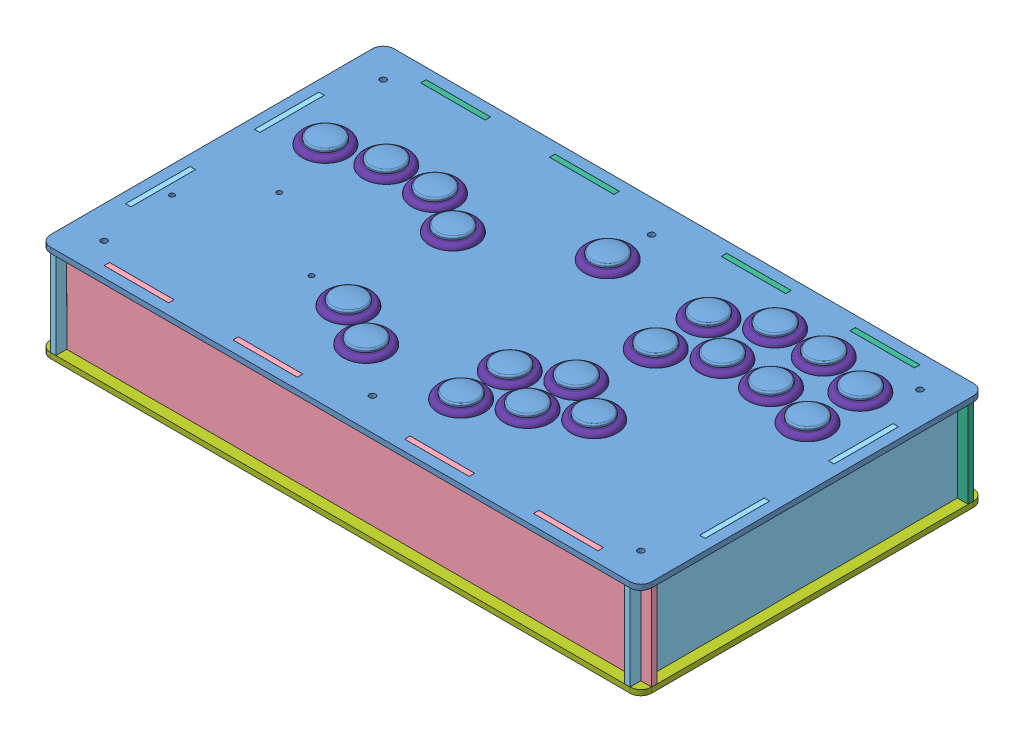
SolidWorks assembly Case v0, configuration Default. Lengths in mm.
Overall size (355.6 62.95 203.2).
164 component instances, 43 part files, 90 mates.
Components (placement in the parent):
- Top Panel-1: Top Panel [Default] at (-41.3019 22.3598 7.6821) size (355.6 3.17 203.2)
- arduino_MEGA2560.STEP-1: arduino_MEGA2560.STEP [Default] at (-106.9007 4.8848 49.2821) x (0 0 1) z (1 0 0) size (53.34 15.25 107.96)
  - MEGAboard.STEP-1: MEGAboard.STEP [Default] at origin size (53.34 1.6 101.6)
  - 47uf CAP Dcase.STEP-1: 47uf CAP Dcase.STEP [Default] at (-9.144 0 -18.415) x (0 0 -1) z (1 0 0) size (7.2 5.81 8)
  - USB SHELL.STEP-1: USB SHELL.STEP [Default] at (-38.02 0.43 6.35) size (14.09 15.2 16.51)
  - USB core.STEP-1: USB core.STEP [Default] at (-38.02 0.43 6.35) size (11.3 10.68 15.75)
  - usb top contact.STEP-1: usb top contact.STEP [Default] at (-36.77 6.52 5.97) size (1 9.67 13.76)
  - usb btm contact.STEP-1: usb btm contact.STEP [Default] at (-36.77 4.84 5.97) size (1 6.84 11.76)
  - usb btm contact.STEP-2: usb btm contact.STEP [Default] at (-39.27 4.84 5.97) size (1 6.84 11.76)
  - usb top contact.STEP-2: usb top contact.STEP [Default] at (-39.27 6.52 5.97) size (1 9.67 13.76)
  - power jack.STEP-1: power jack.STEP [Default] at (-7.675 0 1.905) size (11.2 15.2 15.9)
  - 47uf CAP Dcase.STEP-2: 47uf CAP Dcase.STEP [Default] at (-9.144 0 -25.527) x (0 0 -1) z (1 0 0) size (7.2 5.81 8)
  - crystal.STEP-1: crystal.STEP [Default] at (-26.035 0 -18.415) x (1 0 0) z (0 0 -1) size (4 5 11)
  - 2pin_header__02.STEP-1: 2pin_header__02.STEP [Default] at (-46.23 0 -15.75) size (5 11.75 2.54)
  - reg.STEP-1: reg.STEP [Default] at (-17.78 0 -8.636) size (6.5 1.69 8.3)
  - led.STEP-1: led.STEP [Default] at (-34.29 0 -27.94) x (0 0 1) z (-1 0 0) size (4.01 0.9 1.56)
  - 2pin_header__02.STEP-2: 2pin_header__02.STEP [Default] at (-30.43 0 -64.91) x (0 0 1) z (-1 0 0) size (5 11.75 2.54)
  - 2pin_header__02.STEP-3: 2pin_header__02.STEP [Default] at (-27.89 0 -64.91) x (0 0 1) z (-1 0 0) size (5 11.75 2.54)
  - 2pin_header__02.STEP-4: 2pin_header__02.STEP [Default] at (-25.35 0 -64.91) x (0 0 1) z (-1 0 0) size (5 11.75 2.54)
  - 2pin_header__02.STEP-5: 2pin_header__02.STEP [Default] at (-46.23 0 -18.29) size (5 11.75 2.54)
  - 2pin_header__02.STEP-6: 2pin_header__02.STEP [Default] at (-46.23 0 -20.83) size (5 11.75 2.54)
  - atmega16u2.STEP-1: atmega16u2.STEP [Default] at (-34.671 0.06 -20) x (1 0 0) z (0 0 -1) size (5.5 1.01 5.5)
  - led.STEP-2: led.STEP [Default] at (-36.576 0 -27.94) x (0 0 -1) z (1 0 0) size (4.01 0.9 1.56)
  - led.STEP-3: led.STEP [Default] at (-42.164 0 -27.94) x (0 0 1) z (-1 0 0) size (4.01 0.9 1.56)
  - led.STEP-4: led.STEP [Default] at (-36.83 0 -76.2) x (0 0 1) z (-1 0 0) size (4.01 0.9 1.56)
  - 8 PORT HEADER.STEP-1: 8 PORT HEADER.STEP [Default] at (-50.8 0 -45.72) x (0 0 -1) z (1 0 0) size (20.32 10.51 2.41)
  - 8 PORT HEADER.STEP-2: 8 PORT HEADER.STEP [Default] at (-2.54 0 -27.94) x (0 0 -1) z (1 0 0) size (20.32 10.51 2.41)
  - 8 PORT HEADER.STEP-3: 8 PORT HEADER.STEP [Default] at (-2.54 0 -50.8) x (0 0 -1) z (1 0 0) size (20.32 10.51 2.41)
  - 10 PORT HEADER.STEP-1: 10 PORT HEADER.STEP [Default] at (-50.8 0 -18.796) x (0 0 -1) z (1 0 0) size (25.4 10.51 2.41)
  - 102 RESISTOR PACK.STEP-1: 102 RESISTOR PACK.STEP [Default] at (-36.83 0 -80.645) size (3.2 0.51 3)
  - 102 RESISTOR PACK.STEP-2: 102 RESISTOR PACK.STEP [Default] at (-39.37 0 -27.94) size (3.2 0.51 3)
  - 103 RESISTOR PACK.STEP-1: 103 RESISTOR PACK.STEP [Default] at (-31.115 0 -27.94) size (3.2 0.51 3)
  - 220 RESISTOR PACK.STEP-1: 220 RESISTOR PACK.STEP [Default] at (-37.084 0 -12.065) size (3.2 0.51 3)
  - 16mhz crystal - measured.STEP-1: 16mhz crystal - measured.STEP [Default] at (-14.605 0 -38.354) size (3.4 0.8 2)
  - PADS001.STEP-1: PADS001.STEP [Default] at (-39.878 0.1 -18.288) x (-1 0 0) z (0 0 1) size (4.54 0.1 4.54)
  - 603 cap on pad.STEP-1: 603 cap on pad.STEP [Default] at (-44.45 0 -27.94) x (0 0 -1) z (1 0 0) size (2.76 0.9 1.02)
  - ssot3.STEP-1: ssot3.STEP [Default] at (-25.908 0 -9.144) x (-1 0 0) z (0 0 -1) size (3 1.13 3.09)
  - mf-msmf050-2.STEP-1: mf-msmf050-2.STEP [Default] at (-26.67 0 -4.445) size (6.12 1.1 3.72)
  - 603 cap on pad.STEP-2: 603 cap on pad.STEP [Default] at (-29.337 0 -24.765) x (0 0 1) z (-1 0 0) size (2.76 0.9 1.02)
  - 603 cap on pad.STEP-3: 603 cap on pad.STEP [Default] at (-30.988 0 -12.065) x (0 0 -1) z (1 0 0) size (2.76 0.9 1.02)
  - lmv358.STEP-1: lmv358.STEP [Default] at (-25.146 0 -27.94) size (3.7 1.4 2.9)
  - 603 cap on pad.STEP-4: 603 cap on pad.STEP [Default] at (-17.653 0 -14.351) size (2.76 0.9 1.02)
  - 603 cap on pad.STEP-5: 603 cap on pad.STEP [Default] at (-29.337 0 -12.065) x (0 0 1) z (-1 0 0) size (2.76 0.9 1.02)
  - 603 cap on pad.STEP-6: 603 cap on pad.STEP [Default] at (-29.337 0 -21.59) x (0 0 1) z (-1 0 0) size (2.76 0.9 1.02)
  - 603 cap on pad.STEP-7: 603 cap on pad.STEP [Default] at (-29.337 0 -15.24) x (0 0 1) z (-1 0 0) size (2.76 0.9 1.02)
  - 603 cap on pad.STEP-8: 603 cap on pad.STEP [Default] at (-42.291 0 -12.065) x (0 0 1) z (-1 0 0) size (2.76 0.9 1.02)
  - lp2985dgkr.STEP-1: lp2985dgkr.STEP [Default] at (-21.336 0 -18.415) x (0 0 -1) z (1 0 0) size (5.85 1.1 3)
  - cd1206 diode.STEP-1: cd1206 diode.STEP [Default] at (-14.605 0 -35.56) x (0 0 1) z (-1 0 0) size (2.01 0.96 5)
  - cd1206 diode.STEP-2: cd1206 diode.STEP [Default] at (-46.228 0 -13.081) x (0 0 1) z (-1 0 0) size (2.01 0.96 5)
  - 603 resistor.STEP-1: 603 resistor.STEP [Default] at (-29.337 0 -18.415) x (0 0 1) z (-1 0 0) size (2.36 0.61 1.02)
  - blm21.STEP-1: blm21.STEP [Default] at (-45.085 0 -8.255) x (0 0 -1) z (1 0 0) size (2.78 0.95 1.32)
  - m7 diode.STEP-1: m7 diode.STEP [Default] at (-2.794 0 -21.59) x (0 0 -1) z (1 0 0) size (6.66 2.35 2.5)
  - MLC0603.STEP-1: MLC0603.STEP [Default] at (-34.29 0 -12.065) x (0 0 -1) z (1 0 0) size (2.36 0.6 1.02)
  - MLC0603.STEP-2: MLC0603.STEP [Default] at (-39.878 0 -12.065) x (0 0 -1) z (1 0 0) size (2.36 0.6 1.02)
  - RESET CORE.STEP-1: RESET CORE.STEP [Default] at (-27.94 0.1 -74.168) x (0 0 1) z (-1 0 0) size (6.2 3.1 9.6)
  - RESET.STEP-1: RESET.STEP [Default] at (-27.94 0.1 -74.168) size (7.3 2 6.2)
  - 8 PORT HEADER.STEP-4: 8 PORT HEADER.STEP [Default] at (-2.54 0 -73.66) x (0 0 -1) z (1 0 0) size (20.32 10.51 2.41)
  - 8 PORT HEADER.STEP-5: 8 PORT HEADER.STEP [Default] at (-50.8 0 -68.58) x (0 0 -1) z (1 0 0) size (20.32 10.51 2.41)
  - 603 cap on pad.STEP-9: 603 cap on pad.STEP [Default] at (-21.59 0 -27.94) x (0 0 1) z (-1 0 0) size (2.76 0.9 1.02)
  - 603 cap on pad.STEP-10: 603 cap on pad.STEP [Default] at (-18.288 0 -27.94) x (0 0 1) z (-1 0 0) size (2.76 0.9 1.02)
  - 103 RESISTOR PACK.STEP-2: 103 RESISTOR PACK.STEP [Default] at (-16.51 0 -18.415) size (3.2 0.51 3)
  - 603 cap on pad.STEP-11: 603 cap on pad.STEP [Default] at (-17.145 0 -21.59) x (0 0 -1) z (1 0 0) size (2.76 0.9 1.02)
  - 603 cap on pad.STEP-12: 603 cap on pad.STEP [Default] at (-39.37 0 -58.928) x (0 0 1) z (-1 0 0) size (2.76 0.9 1.02)
  - 603 cap on pad.STEP-13: 603 cap on pad.STEP [Default] at (-14.605 0 -33.528) size (2.76 0.9 1.02)
  - 603 resistor.STEP-2: 603 resistor.STEP [Default] at (-14.605 0 -40.513) x (-1 0 0) z (0 0 -1) size (2.36 0.61 1.02)
  - 603 cap on pad.STEP-14: 603 cap on pad.STEP [Default] at (-7.112 0 -38.608) x (0 0 1) z (-1 0 0) size (2.76 0.9 1.02)
  - 603 cap on pad.STEP-15: 603 cap on pad.STEP [Default] at (-30.4038 0 -40.0558) x (0 0 1) z (-1 0 0) size (2.76 0.9 1.02)
  - 18 X 2 ROW HEADER.STEP-1: 18 X 2 ROW HEADER.STEP [Default] at (-50.8 0 -95.25) size (45.72 10.51 4.95)
  - atmega2650-16AU.STEP-1: atmega2650-16AU.STEP [Default] at (-28.3464 0.1 -50.8) x (0 0 1) z (-1 0 0) size (16.81 1.11 16.81)
- Sanwa OBSF 24mm button.step-1: Sanwa OBSF 24mm button.step [Default] at (-183.9019 8.6598 -24.5179) x (1 0 0) z (0 1 0) size (27.2 29.72 39.22)
  - Base.step-1: Base.step [Default] at origin size (27.2 29.72 21)
  - microswitch v2.step-1: microswitch v2.step [Default] at (0 0 -9.176) size (15.01 12.06 29.85)
  - Top cap.step-1: Top cap.step [Default] at origin size (24 19.5 12.44)
- Sanwa OBSF 24mm button.step-2: Sanwa OBSF 24mm button.step [Default] at (-155.1019 8.6598 -31.7179) x (1 0 0) z (0 1 0) size (27.2 29.72 39.22)
  - Base.step-1: Base.step [Default] at origin size (27.2 29.72 21)
  - microswitch v2.step-1: microswitch v2.step [Default] at (0 0 -9.176) size (15.01 12.06 29.85)
  - Top cap.step-1: Top cap.step [Default] at origin size (24 19.5 12.44)
- Sanwa OBSF 24mm button.step-3: Sanwa OBSF 24mm button.step [Default] at (-126.3019 8.6598 -31.7179) x (1 0 0) z (0 1 0) size (27.2 29.72 39.22)
  - Base.step-1: Base.step [Default] at origin size (27.2 29.72 21)
  - microswitch v2.step-1: microswitch v2.step [Default] at (0 0 -9.176) size (15.01 12.06 29.85)
  - Top cap.step-1: Top cap.step [Default] at origin size (24 19.5 12.44)
- Sanwa OBSF 24mm button.step-4: Sanwa OBSF 24mm button.step [Default] at (-101.3019 8.6598 -17.3179) x (1 0 0) z (0 1 0) size (27.2 29.72 39.22)
  - Base.step-1: Base.step [Default] at origin size (27.2 29.72 21)
  - microswitch v2.step-1: microswitch v2.step [Default] at (0 0 -9.176) size (15.01 12.06 29.85)
  - Top cap.step-1: Top cap.step [Default] at origin size (24 19.5 12.44)
- Sanwa OBSF 24mm button.step-5: Sanwa OBSF 24mm button.step [Default] at (-94.3019 8.6598 51.4821) x (1 0 0) z (0 1 0) size (27.2 29.72 39.22)
  - Base.step-1: Base.step [Default] at origin size (27.2 29.72 21)
  - microswitch v2.step-1: microswitch v2.step [Default] at (0 0 -9.176) size (15.01 12.06 29.85)
  - Top cap.step-1: Top cap.step [Default] at origin size (24 19.5 12.44)
- Sanwa OBSF 24mm button.step-6: Sanwa OBSF 24mm button.step [Default] at (-69.3604 8.6598 65.8821) x (1 0 0) z (0 1 0) size (27.2 29.72 39.22)
  - Base.step-1: Base.step [Default] at origin size (27.2 29.72 21)
  - microswitch v2.step-1: microswitch v2.step [Default] at (0 0 -9.176) size (15.01 12.06 29.85)
  - Top cap.step-1: Top cap.step [Default] at origin size (24 19.5 12.44)
- Sanwa OBSF 24mm button.step-7: Sanwa OBSF 24mm button.step [Default] at (-41.3019 8.6598 -48.9179) x (1 0 0) z (0 1 0) size (27.2 29.72 39.22)
  - Base.step-1: Base.step [Default] at origin size (27.2 29.72 21)
  - microswitch v2.step-1: microswitch v2.step [Default] at (0 0 -9.176) size (15.01 12.06 29.85)
  - Top cap.step-1: Top cap.step [Default] at origin size (24 19.5 12.44)
- Sanwa OBSF 24mm button.step-8: Sanwa OBSF 24mm button.step [Default] at (-13.2435 8.6598 65.8821) x (-1 0 0) z (0 1 0) size (27.2 29.72 39.22)
  - Base.step-1: Base.step [Default] at origin size (27.2 29.72 21)
  - microswitch v2.step-1: microswitch v2.step [Default] at (0 0 -9.176) size (15.01 12.06 29.85)
  - Top cap.step-1: Top cap.step [Default] at origin size (24 19.5 12.44)
- Sanwa OBSF 24mm button.step-9: Sanwa OBSF 24mm button.step [Default] at (-13.2435 8.6598 37.0821) x (1 0 0) z (0 1 0) size (27.2 29.72 39.22)
  - Base.step-1: Base.step [Default] at origin size (27.2 29.72 21)
  - microswitch v2.step-1: microswitch v2.step [Default] at (0 0 -9.176) size (15.01 12.06 29.85)
  - Top cap.step-1: Top cap.step [Default] at origin size (24 19.5 12.44)
- Sanwa OBSF 24mm button.step-10: Sanwa OBSF 24mm button.step [Default] at (11.6981 8.6598 51.4821) x (1 0 0) z (0 1 0) size (27.2 29.72 39.22)
  - Base.step-1: Base.step [Default] at origin size (27.2 29.72 21)
  - microswitch v2.step-1: microswitch v2.step [Default] at (0 0 -9.176) size (15.01 12.06 29.85)
  - Top cap.step-1: Top cap.step [Default] at origin size (24 19.5 12.44)
- Sanwa OBSF 24mm button.step-11: Sanwa OBSF 24mm button.step [Default] at (36.6396 8.6598 37.0821) x (1 0 0) z (0 1 0) size (27.2 29.72 39.22)
  - Base.step-1: Base.step [Default] at origin size (27.2 29.72 21)
  - microswitch v2.step-1: microswitch v2.step [Default] at (0 0 -9.176) size (15.01 12.06 29.85)
  - Top cap.step-1: Top cap.step [Default] at origin size (24 19.5 12.44)
- Sanwa OBSF 24mm button.step-12: Sanwa OBSF 24mm button.step [Default] at (11.6981 8.6598 22.6821) x (1 0 0) z (0 1 0) size (27.2 29.72 39.22)
  - Base.step-1: Base.step [Default] at origin size (27.2 29.72 21)
  - microswitch v2.step-1: microswitch v2.step [Default] at (0 0 -9.176) size (15.01 12.06 29.85)
  - Top cap.step-1: Top cap.step [Default] at origin size (24 19.5 12.44)
- Sanwa OBSF 24mm button.step-13: Sanwa OBSF 24mm button.step [Default] at (18.6981 8.6598 -17.3179) x (-1 0 0) z (0 1 0) size (27.2 29.72 39.22)
  - Base.step-1: Base.step [Default] at origin size (27.2 29.72 21)
  - microswitch v2.step-1: microswitch v2.step [Default] at (0 0 -9.176) size (15.01 12.06 29.85)
  - Top cap.step-1: Top cap.step [Default] at origin size (24 19.5 12.44)
- Sanwa OBSF 24mm button.step-14: Sanwa OBSF 24mm button.step [Default] at (18.6981 8.6598 -48.5179) x (-1 0 0) z (0 1 0) size (27.2 29.72 39.22)
  - Base.step-1: Base.step [Default] at origin size (27.2 29.72 21)
  - microswitch v2.step-1: microswitch v2.step [Default] at (0 0 -9.176) size (15.01 12.06 29.85)
  - Top cap.step-1: Top cap.step [Default] at origin size (24 19.5 12.44)
- Sanwa OBSF 24mm button.step-15: Sanwa OBSF 24mm button.step [Default] at (43.6981 8.6598 -31.7179) x (-1 0 0) z (0 1 0) size (27.2 29.72 39.22)
  - Base.step-1: Base.step [Default] at origin size (27.2 29.72 21)
  - microswitch v2.step-1: microswitch v2.step [Default] at (0 0 -9.176) size (15.01 12.06 29.85)
  - Top cap.step-1: Top cap.step [Default] at origin size (24 19.5 12.44)
- Sanwa OBSF 24mm button.step-16: Sanwa OBSF 24mm button.step [Default] at (72.4981 8.6598 -31.7179) x (-1 0 0) z (0 1 0) size (27.2 29.72 39.22)
  - Base.step-1: Base.step [Default] at origin size (27.2 29.72 21)
  - microswitch v2.step-1: microswitch v2.step [Default] at (0 0 -9.176) size (15.01 12.06 29.85)
  - Top cap.step-1: Top cap.step [Default] at origin size (24 19.5 12.44)
- Sanwa OBSF 24mm button.step-17: Sanwa OBSF 24mm button.step [Default] at (101.2981 8.6598 -24.5179) x (-1 0 0) z (0 1 0) size (27.2 29.72 39.22)
  - Base.step-1: Base.step [Default] at origin size (27.2 29.72 21)
  - microswitch v2.step-1: microswitch v2.step [Default] at (0 0 -9.176) size (15.01 12.06 29.85)
  - Top cap.step-1: Top cap.step [Default] at origin size (24 19.5 12.44)
- Sanwa OBSF 24mm button.step-18: Sanwa OBSF 24mm button.step [Default] at (101.2981 8.6598 -55.7179) x (-1 0 0) z (0 1 0) size (27.2 29.72 39.22)
  - Base.step-1: Base.step [Default] at origin size (27.2 29.72 21)
  - microswitch v2.step-1: microswitch v2.step [Default] at (0 0 -9.176) size (15.01 12.06 29.85)
  - Top cap.step-1: Top cap.step [Default] at origin size (24 19.5 12.44)
- Sanwa OBSF 24mm button.step-19: Sanwa OBSF 24mm button.step [Default] at (72.4981 8.6598 -62.9179) x (-1 0 0) z (0 1 0) size (27.2 29.72 39.22)
  - Base.step-1: Base.step [Default] at origin size (27.2 29.72 21)
  - microswitch v2.step-1: microswitch v2.step [Default] at (0 0 -9.176) size (15.01 12.06 29.85)
  - Top cap.step-1: Top cap.step [Default] at origin size (24 19.5 12.44)
- Sanwa OBSF 24mm button.step-20: Sanwa OBSF 24mm button.step [Default] at (43.6981 8.6598 -62.9179) x (-1 0 0) z (0 1 0) size (27.2 29.72 39.22)
  - Base.step-1: Base.step [Default] at origin size (27.2 29.72 21)
  - microswitch v2.step-1: microswitch v2.step [Default] at (0 0 -9.176) size (15.01 12.06 29.85)
  - Top cap.step-1: Top cap.step [Default] at origin size (24 19.5 12.44)
- 91780A339_Female Threaded Hex Standoff-1: 91780A339_Female Threaded Hex Standoff [91780A339] at (117.4481 -6.2152 90.2321) x (1 0 0) z (0 1 0) size (6.35 7.33 51.4)
- 91780A339_Female Threaded Hex Standoff-2: 91780A339_Female Threaded Hex Standoff [91780A339] at (-41.3019 -6.2152 90.2321) x (1 0 0) z (0 1 0) size (6.35 7.33 51.4)
- 91780A339_Female Threaded Hex Standoff-3: 91780A339_Female Threaded Hex Standoff [91780A339] at (-200.0519 -6.2152 90.2321) x (0.18551 0 -0.982642) z (0 1 0) size (6.35 7.33 51.4)
- 91780A339_Female Threaded Hex Standoff-4: 91780A339_Female Threaded Hex Standoff [91780A339] at (-200.0519 -6.2152 -74.8679) x (1 0 0) z (0 -1 0) size (6.35 7.33 51.4)
- 91780A339_Female Threaded Hex Standoff-5: 91780A339_Female Threaded Hex Standoff [91780A339] at (-41.3019 -6.2152 -74.8679) x (1 0 0) z (0 -1 0) size (6.35 7.33 51.4)
- 91780A339_Female Threaded Hex Standoff-6: 91780A339_Female Threaded Hex Standoff [91780A339] at (117.4481 -6.2152 -74.8679) x (1 0 0) z (0 -1 0) size (6.35 7.33 51.4)
- 91780A533_Female Threaded Hex Standoff-1: 91780A533_Female Threaded Hex Standoff [91780A533] at (-120.8707 12.8348 46.7421) x (1 0 0) z (0 -1 0) size (4.76 5.5 13.2)
- 91780A533_Female Threaded Hex Standoff-2: 91780A533_Female Threaded Hex Standoff [91780A533] at (-172.9407 12.8348 41.6621) x (1 0 0) z (0 -1 0) size (4.76 5.5 13.2)
- 91780A533_Female Threaded Hex Standoff-3: 91780A533_Female Threaded Hex Standoff [91780A533] at (-172.9407 12.8348 13.7221) x (0.649448 0 0.760406) z (0 -1 0) size (4.76 5.5 13.2)
- 91780A533_Female Threaded Hex Standoff-4: 91780A533_Female Threaded Hex Standoff [91780A533] at (-203.4207 12.8348 46.7421) x (0.649448 0 0.760406) z (0 -1 0) size (4.76 5.5 13.2)
- Bottom Panel-1: Bottom Panel [Default] at (-219.1019 -31.6152 99.7196) size (355.6 57.15 3.17)
- Side Panel-1: Side Panel [Default] at (130.11 19.1848 109.2821) x (0 0 -1) z (-1 0 0) size (203.2 57.15 3.17)
- Side Panel-2: Side Panel [Default] at (-209.5388 19.1848 109.2821) x (0 0 -1) z (-1 0 0) size (203.2 57.15 3.17)
- Connector Panel-1: Connector Panel [Default] at (-219.1019 -31.6152 -87.5304) size (355.6 57.15 3.17)
- Base Panel-1: Base Panel [Default] at (-41.3019 -31.6152 7.6821) size (355.6 3.17 203.2)
Mates (geometry in assembly coordinates):
- Concentric1: concentric aligned: cylinder of Top Panel-1 through (-200.0519 12.3598 -74.8679) axis (0 1 0) radius 1.8288; circle of 91780A337_Female Threaded Hex Standoff-1
- Coincident1: coincident anti-aligned: plane of Top Panel-1 through (-41.3019 19.1848 7.6821) normal (0 -1 0); plane of 91780A337_Female Threaded Hex Standoff-1 through (-207.171 19.1848 -77.6333) normal (0 1 0)
- Concentric2: concentric aligned: cylinder of Top Panel-1 through (-41.3019 12.3598 -74.8679) axis (0 1 0) radius 1.8288; circle of 91780A337_Female Threaded Hex Standoff-2
- Coincident2: coincident anti-aligned: plane of Top Panel-1 through (-41.3019 19.1848 7.6821) normal (0 -1 0); plane of 91780A337_Female Threaded Hex Standoff-2 through (-42.071 19.1848 -77.6333) normal (0 1 0)
- Concentric3: concentric aligned: cylinder of Top Panel-1 through (117.4481 12.3598 -74.8679) axis (0 1 0) radius 1.8288; circle of 91780A337_Female Threaded Hex Standoff-3
- Coincident3: coincident anti-aligned: plane of Top Panel-1 through (-41.3019 19.1848 7.6821) normal (0 -1 0); plane of 91780A337_Female Threaded Hex Standoff-3 through (123.029 19.1848 -77.6333) normal (0 1 0)
- Concentric4: concentric aligned: cylinder of Top Panel-1 through (117.4481 12.3598 90.2321) axis (0 1 0) radius 1.8288; circle of 91780A337_Female Threaded Hex Standoff-4
- Coincident4: coincident anti-aligned: plane of Top Panel-1 through (-41.3019 19.1848 7.6821) normal (0 -1 0); plane of 91780A337_Female Threaded Hex Standoff-4 through (123.029 19.1848 100.1667) normal (0 1 0)
- Concentric5: concentric aligned: cylinder of Top Panel-1 through (-41.3019 12.3598 90.2321) axis (0 1 0) radius 1.8288; circle of 91780A337_Female Threaded Hex Standoff-5
- Coincident5: coincident anti-aligned: plane of Top Panel-1 through (-41.3019 19.1848 7.6821) normal (0 -1 0); plane of 91780A337_Female Threaded Hex Standoff-5 through (-42.071 19.1848 100.1667) normal (0 1 0)
- Concentric6: concentric aligned: cylinder of Top Panel-1 through (-200.0519 12.3598 90.2321) axis (0 1 0) radius 1.8288; circle of 91780A337_Female Threaded Hex Standoff-6
- Coincident6: coincident anti-aligned: plane of Top Panel-1 through (-41.3019 19.1848 7.6821) normal (0 -1 0); plane of 91780A337_Female Threaded Hex Standoff-6 through (-207.171 19.1848 100.1667) normal (0 1 0)
- Concentric7: concentric aligned: cylinder of Top Panel-1 through (-183.9019 19.1848 -24.5179) axis (0 1 0) radius 12; cylinder of Sanwa OBSF 24mm button.step-1/Base.step-1 through (-183.9019 15.5098 -24.5179) axis (0 1 0) radius 11.75
- Concentric8: concentric aligned: cylinder of Top Panel-1 through (-155.1019 19.1848 -31.7179) axis (0 1 0) radius 12; cylinder of Sanwa OBSF 24mm button.step-2/Base.step-1 through (-155.1019 15.5098 -31.7179) axis (0 1 0) radius 11.75
- Concentric9: concentric aligned: cylinder of Top Panel-1 through (-126.3019 19.1848 -31.7179) axis (0 1 0) radius 12; cylinder of Sanwa OBSF 24mm button.step-3/Base.step-1 through (-126.3019 15.5098 -31.7179) axis (0 1 0) radius 11.75
- Concentric11: concentric aligned: cylinder of Top Panel-1 through (-101.3019 19.1848 -17.3179) axis (0 1 0) radius 12; cylinder of Sanwa OBSF 24mm button.step-4/Base.step-1 through (-101.3019 15.5098 -17.3179) axis (0 1 0) radius 11.75
- Concentric12: concentric aligned: cylinder of Top Panel-1 through (-94.3019 19.1848 51.4821) axis (0 1 0) radius 12; cylinder of Sanwa OBSF 24mm button.step-5/Base.step-1 through (-94.3019 15.5098 51.4821) axis (0 1 0) radius 11.75
- Concentric13: concentric aligned: cylinder of Top Panel-1 through (-69.3604 19.1848 65.8821) axis (0 1 0) radius 12; cylinder of Sanwa OBSF 24mm button.step-6/Base.step-1 through (-69.3604 15.5098 65.8821) axis (0 1 0) radius 11.75
- Concentric14: concentric aligned: cylinder of Top Panel-1 through (-41.3019 19.1848 -48.9179) axis (0 1 0) radius 12; cylinder of Sanwa OBSF 24mm button.step-7/Base.step-1 through (-41.3019 15.5098 -48.9179) axis (0 1 0) radius 11.75
- Concentric15: concentric aligned: cylinder of Top Panel-1 through (-13.2435 19.1848 65.8821) axis (0 1 0) radius 12; cylinder of Sanwa OBSF 24mm button.step-8/Base.step-1 through (-13.2435 15.5098 65.8821) axis (0 1 0) radius 11.75
- Concentric16: concentric aligned: cylinder of Top Panel-1 through (-13.2435 19.1848 37.0821) axis (0 1 0) radius 12; cylinder of Sanwa OBSF 24mm button.step-9/Base.step-1 through (-13.2435 15.5098 37.0821) axis (0 1 0) radius 11.75
- Concentric17: concentric aligned: cylinder of Top Panel-1 through (11.6981 19.1848 51.4821) axis (0 1 0) radius 12; cylinder of Sanwa OBSF 24mm button.step-10/Base.step-1 through (11.6981 15.5098 51.4821) axis (0 1 0) radius 11.75
- Concentric18: concentric aligned: cylinder of Top Panel-1 through (36.6396 19.1848 37.0821) axis (0 1 0) radius 12; cylinder of Sanwa OBSF 24mm button.step-11/Base.step-1 through (36.6396 15.5098 37.0821) axis (0 1 0) radius 11.75
- Concentric19: concentric aligned: cylinder of Top Panel-1 through (11.6981 19.1848 22.6821) axis (0 1 0) radius 12; cylinder of Sanwa OBSF 24mm button.step-12/Base.step-1 through (11.6981 15.5098 22.6821) axis (0 1 0) radius 11.75
- Concentric20: concentric anti-aligned: cylinder of Top Panel-1 through (18.6981 22.3598 -17.3179) axis (0 -1 0) radius 12; cylinder of Sanwa OBSF 24mm button.step-13/Base.step-1 through (18.6981 15.5098 -17.3179) axis (0 1 0) radius 11.75
- Concentric21: concentric anti-aligned: cylinder of Top Panel-1 through (18.6981 22.3598 -48.5179) axis (0 -1 0) radius 12; cylinder of Sanwa OBSF 24mm button.step-14/Base.step-1 through (18.6981 15.5098 -48.5179) axis (0 1 0) radius 11.75
- Concentric22: concentric anti-aligned: cylinder of Top Panel-1 through (43.6981 22.3598 -31.7179) axis (0 -1 0) radius 12; cylinder of Sanwa OBSF 24mm button.step-15/Base.step-1 through (43.6981 15.5098 -31.7179) axis (0 1 0) radius 11.75
- Concentric23: concentric anti-aligned: cylinder of Top Panel-1 through (72.4981 22.3598 -31.7179) axis (0 -1 0) radius 12; cylinder of Sanwa OBSF 24mm button.step-16/Base.step-1 through (72.4981 15.5098 -31.7179) axis (0 1 0) radius 11.75
- Concentric24: concentric anti-aligned: cylinder of Top Panel-1 through (101.2981 22.3598 -24.5179) axis (0 -1 0) radius 12; cylinder of Sanwa OBSF 24mm button.step-17/Base.step-1 through (101.2981 15.5098 -24.5179) axis (0 1 0) radius 11.75
- Concentric25: concentric anti-aligned: cylinder of Top Panel-1 through (101.2981 22.3598 -55.7179) axis (0 -1 0) radius 12; cylinder of Sanwa OBSF 24mm button.step-18/Base.step-1 through (101.2981 15.5098 -55.7179) axis (0 1 0) radius 11.75
- Concentric26: concentric anti-aligned: cylinder of Top Panel-1 through (72.4981 22.3598 -62.9179) axis (0 -1 0) radius 12; cylinder of Sanwa OBSF 24mm button.step-19/Base.step-1 through (72.4981 15.5098 -62.9179) axis (0 1 0) radius 11.75
- Concentric27: concentric anti-aligned: cylinder of Top Panel-1 through (43.6981 22.3598 -62.9179) axis (0 -1 0) radius 12; cylinder of Sanwa OBSF 24mm button.step-20/Base.step-1 through (43.6981 15.5098 -62.9179) axis (0 1 0) radius 11.75
- Coincident9: coincident anti-aligned: plane of Top Panel-1 through (-41.3019 22.3598 7.6821) normal (0 1 0); plane of Sanwa OBSF 24mm button.step-18/Base.step-1 through (87.6981 22.3598 -55.7179) normal (0 -1 0)
- Coincident10: coincident anti-aligned: plane of Top Panel-1 through (-41.3019 22.3598 7.6821) normal (0 1 0); plane of Sanwa OBSF 24mm button.step-19/Base.step-1 through (58.8981 22.3598 -62.9179) normal (0 -1 0)
- Coincident11: coincident anti-aligned: plane of Top Panel-1 through (-41.3019 22.3598 7.6821) normal (0 1 0); plane of Sanwa OBSF 24mm button.step-20/Base.step-1 through (30.0981 22.3598 -62.9179) normal (0 -1 0)
- Coincident12: coincident anti-aligned: plane of Top Panel-1 through (-41.3019 22.3598 7.6821) normal (0 1 0); plane of Sanwa OBSF 24mm button.step-14/Base.step-1 through (5.0981 22.3598 -48.5179) normal (0 -1 0)
- Coincident13: coincident anti-aligned: plane of Top Panel-1 through (-41.3019 22.3598 7.6821) normal (0 1 0); plane of Sanwa OBSF 24mm button.step-17/Base.step-1 through (87.6981 22.3598 -24.5179) normal (0 -1 0)
- Coincident14: coincident anti-aligned: plane of Top Panel-1 through (-41.3019 22.3598 7.6821) normal (0 1 0); plane of Sanwa OBSF 24mm button.step-16/Base.step-1 through (58.8981 22.3598 -31.7179) normal (0 -1 0)
- Coincident15: coincident anti-aligned: plane of Top Panel-1 through (-41.3019 22.3598 7.6821) normal (0 1 0); plane of Sanwa OBSF 24mm button.step-15/Base.step-1 through (30.0981 22.3598 -31.7179) normal (0 -1 0)
- Coincident16: coincident anti-aligned: plane of Top Panel-1 through (-41.3019 22.3598 7.6821) normal (0 1 0); plane of Sanwa OBSF 24mm button.step-13/Base.step-1 through (5.0981 22.3598 -17.3179) normal (0 -1 0)
- Coincident23: coincident anti-aligned: plane of Top Panel-1 through (-41.3019 22.3598 7.6821) normal (0 1 0); plane of Sanwa OBSF 24mm button.step-4/Base.step-1 through (-87.7019 22.3598 -17.3179) normal (0 -1 0)
- Coincident25: coincident anti-aligned: plane of Top Panel-1 through (-41.3019 22.3598 7.6821) normal (0 1 0); plane of Sanwa OBSF 24mm button.step-3/Base.step-1 through (-112.7019 22.3598 -31.7179) normal (0 -1 0)
- Coincident29: coincident anti-aligned: plane of Top Panel-1 through (-41.3019 22.3598 7.6821) normal (0 1 0); plane of Sanwa OBSF 24mm button.step-2/Base.step-1 through (-141.5019 22.3598 -31.7179) normal (0 -1 0)
- Coincident30: coincident anti-aligned: plane of Top Panel-1 through (-41.3019 22.3598 7.6821) normal (0 1 0); plane of Sanwa OBSF 24mm button.step-1/Base.step-1 through (-170.3019 22.3598 -24.5179) normal (0 -1 0)
- Coincident31: coincident anti-aligned: plane of Top Panel-1 through (-41.3019 22.3598 7.6821) normal (0 1 0); plane of Sanwa OBSF 24mm button.step-5/Base.step-1 through (-80.7019 22.3598 51.4821) normal (0 -1 0)
- Coincident32: coincident anti-aligned: plane of Top Panel-1 through (-41.3019 22.3598 7.6821) normal (0 1 0); plane of Sanwa OBSF 24mm button.step-6/Base.step-1 through (-55.7604 22.3598 65.8821) normal (0 -1 0)
- Coincident34: coincident anti-aligned: plane of Top Panel-1 through (-41.3019 22.3598 7.6821) normal (0 1 0); plane of Sanwa OBSF 24mm button.step-7/Base.step-1 through (-27.7019 22.3598 -48.9179) normal (0 -1 0)
- Coincident36: coincident anti-aligned: plane of Top Panel-1 through (-41.3019 22.3598 7.6821) normal (0 1 0); plane of Sanwa OBSF 24mm button.step-9/Base.step-1 through (0.3565 22.3598 37.0821) normal (0 -1 0)
- Coincident40: coincident anti-aligned: plane of Top Panel-1 through (-41.3019 22.3598 7.6821) normal (0 1 0); plane of Sanwa OBSF 24mm button.step-8/Base.step-1 through (-26.8435 22.3598 65.8821) normal (0 -1 0)
- Coincident42: coincident anti-aligned: plane of Top Panel-1 through (-41.3019 22.3598 7.6821) normal (0 1 0); plane of Sanwa OBSF 24mm button.step-11/Base.step-1 through (50.2396 22.3598 37.0821) normal (0 -1 0)
- Coincident43: coincident anti-aligned: plane of Top Panel-1 through (-41.3019 22.3598 7.6821) normal (0 1 0); plane of Sanwa OBSF 24mm button.step-12/Base.step-1 through (25.2981 22.3598 22.6821) normal (0 -1 0)
- Coincident44: coincident anti-aligned: plane of Top Panel-1 through (-41.3019 19.1848 7.6821) normal (0 -1 0); plane of 91780A339_Female Threaded Hex Standoff-1 through (117.4481 19.1848 86.5659) normal (0 1 0)
- Concentric32: concentric anti-aligned: cylinder of Top Panel-1 through (117.4481 12.3598 90.2321) axis (0 1 0) radius 1.8288; circle of 91780A339_Female Threaded Hex Standoff-1
- Coincident45: coincident anti-aligned: plane of Top Panel-1 through (-41.3019 22.3598 7.6821) normal (0 1 0); plane of Sanwa OBSF 24mm button.step-10/Base.step-1 through (25.2981 22.3598 51.4821) normal (0 -1 0)
- Concentric33: concentric anti-aligned: cylinder of Top Panel-1 through (-41.3019 12.3598 90.2321) axis (0 1 0) radius 1.8288; circle of 91780A339_Female Threaded Hex Standoff-2
- Coincident46: coincident anti-aligned: plane of Top Panel-1 through (-41.3019 19.1848 7.6821) normal (0 -1 0); plane of 91780A339_Female Threaded Hex Standoff-2 through (-41.3019 19.1848 86.5659) normal (0 1 0)
- Concentric34: concentric anti-aligned: cylinder of Top Panel-1 through (-200.0519 12.3598 90.2321) axis (0 1 0) radius 1.8288; circle of 91780A339_Female Threaded Hex Standoff-3
- Coincident47: coincident anti-aligned: plane of Top Panel-1 through (-41.3019 19.1848 7.6821) normal (0 -1 0); plane of 91780A339_Female Threaded Hex Standoff-3 through (-203.6545 19.1848 89.552) normal (0 1 0)
- Concentric35: concentric aligned: cylinder of Top Panel-1 through (-200.0519 12.3598 -74.8679) axis (0 1 0) radius 1.8288; circle of 91780A339_Female Threaded Hex Standoff-4
- Coincident48: coincident anti-aligned: plane of Top Panel-1 through (-41.3019 19.1848 7.6821) normal (0 -1 0); plane of 91780A339_Female Threaded Hex Standoff-4 through (-200.0519 19.1848 -71.2018) normal (0 1 0)
- Concentric36: concentric aligned: cylinder of Top Panel-1 through (-41.3019 12.3598 -74.8679) axis (0 1 0) radius 1.8288; circle of 91780A339_Female Threaded Hex Standoff-5
- Coincident49: coincident anti-aligned: plane of Top Panel-1 through (-41.3019 19.1848 7.6821) normal (0 -1 0); plane of 91780A339_Female Threaded Hex Standoff-5 through (-41.3019 19.1848 -71.2018) normal (0 1 0)
- Concentric37: concentric aligned: circle of 91780A339_Female Threaded Hex Standoff-6; cylinder of Top Panel-1 through (117.4481 12.3598 -74.8679) axis (0 1 0) radius 1.8288
- Coincident50: coincident anti-aligned: plane of Top Panel-1 through (-41.3019 19.1848 7.6821) normal (0 -1 0); plane of 91780A339_Female Threaded Hex Standoff-6 through (117.4481 19.1848 -71.2018) normal (0 1 0)
- Concentric38: concentric anti-aligned: cylinder of arduino_MEGA2560.STEP-1/MEGAboard.STEP-1 through (-120.8707 6.4848 46.7421) axis (0 -1 0) radius 1.5875; circle of 91780A533_Female Threaded Hex Standoff-1
- Coincident51: coincident anti-aligned: plane of arduino_MEGA2560.STEP-1/MEGAboard.STEP-1 through (-106.9007 6.4848 -4.0579) normal (0 1 0); plane of 91780A533_Female Threaded Hex Standoff-1 through (-120.8707 6.4848 49.4917) normal (0 -1 0)
- Concentric39: concentric anti-aligned: cylinder of arduino_MEGA2560.STEP-1/MEGAboard.STEP-1 through (-172.9407 6.4848 41.6621) axis (0 -1 0) radius 1.5875; circle of 91780A533_Female Threaded Hex Standoff-2
- Coincident52: coincident anti-aligned: plane of arduino_MEGA2560.STEP-1/MEGAboard.STEP-1 through (-106.9007 6.4848 -4.0579) normal (0 1 0); plane of 91780A533_Female Threaded Hex Standoff-2 through (-172.9407 6.4848 44.4117) normal (0 -1 0)
- Concentric40: concentric anti-aligned: cylinder of arduino_MEGA2560.STEP-1/MEGAboard.STEP-1 through (-172.9407 6.4848 13.7221) axis (0 -1 0) radius 1.5875; circle of 91780A533_Female Threaded Hex Standoff-3
- Coincident53: coincident anti-aligned: plane of arduino_MEGA2560.STEP-1/MEGAboard.STEP-1 through (-106.9007 6.4848 -4.0579) normal (0 1 0); plane of 91780A533_Female Threaded Hex Standoff-3 through (-175.0316 6.4848 15.5078) normal (0 -1 0)
- Concentric41: concentric anti-aligned: cylinder of arduino_MEGA2560.STEP-1/MEGAboard.STEP-1 through (-203.4207 6.4848 46.7421) axis (0 -1 0) radius 1.5875; circle of 91780A533_Female Threaded Hex Standoff-4
- Coincident54: coincident anti-aligned: plane of arduino_MEGA2560.STEP-1/MEGAboard.STEP-1 through (-106.9007 6.4848 -4.0579) normal (0 1 0); plane of 91780A533_Female Threaded Hex Standoff-4 through (-205.5116 6.4848 48.5278) normal (0 -1 0)
- Coincident55: coincident anti-aligned: plane of Top Panel-1 through (-41.3019 19.1848 7.6821) normal (0 -1 0); plane of 91780A533_Female Threaded Hex Standoff-1 through (-120.8707 19.1848 49.4917) normal (0 1 0)
- Coincident57: coincident anti-aligned: plane of Top Panel-1 through (-41.3019 19.1848 7.6821) normal (0 -1 0); plane of Bottom Panel-1 through (-219.1019 19.1848 102.8946) normal (0 1 0)
- Width1: width anti-aligned: plane of Top Panel-1 through (136.4981 19.1848 -93.9179) normal (1 0 0); plane of Top Panel-1 through (-219.1019 19.1848 -93.9179) normal (-1 0 0); plane of Bottom Panel-1 through (-219.1019 19.1848 102.8946) normal (-1 0 0); plane of Bottom Panel-1 through (136.4981 19.1848 102.8946) normal (1 0 0)
- Width2: width anti-aligned: plane of Top Panel-1 through (104.7881 19.1848 99.6821) normal (0 0 1); plane of Top Panel-1 through (104.7881 19.1848 102.9321) normal (0 0 -1); plane of Bottom Panel-1 through (-219.1019 -31.6152 99.7196) normal (0 0 -1); plane of Bottom Panel-1 through (-219.1019 -31.6152 102.8946) normal (0 0 1)
- Width3: width anti-aligned: plane of Top Panel-1 through (-219.1019 19.1848 109.2821) normal (0 0 1); plane of Top Panel-1 through (-219.1019 19.1848 -93.9179) normal (0 0 -1); plane of Side Panel-1 through (126.935 19.1848 -93.9179) normal (0 0 -1); plane of Side Panel-1 through (126.935 19.1848 109.2821) normal (0 0 1)
- Width4: width anti-aligned: plane of Top Panel-1 through (130.1481 19.1848 -49.506) normal (-1 0 0); plane of Top Panel-1 through (126.8969 19.1848 -49.506) normal (1 0 0); plane of Side Panel-1 through (130.11 19.1848 109.2821) normal (1 0 0); plane of Side Panel-1 through (126.935 19.1848 109.2821) normal (-1 0 0)
- Coincident58: coincident anti-aligned: plane of Top Panel-1 through (-41.3019 19.1848 7.6821) normal (0 -1 0); plane of Side Panel-1 through (126.935 19.1848 109.2821) normal (0 1 0)
- Width5: width anti-aligned: plane of Top Panel-1 through (-209.5007 19.1848 -49.506) normal (-1 0 0); plane of Top Panel-1 through (-212.7519 19.1848 -49.506) normal (1 0 0); plane of Side Panel-2 through (-209.5388 19.1848 109.2821) normal (1 0 0); plane of Side Panel-2 through (-212.7138 19.1848 109.2821) normal (-1 0 0)
- Width6: width anti-aligned: plane of Top Panel-1 through (-219.1019 19.1848 109.2821) normal (0 0 1); plane of Top Panel-1 through (-219.1019 19.1848 -93.9179) normal (0 0 -1); plane of Side Panel-2 through (-212.7138 19.1848 -93.9179) normal (0 0 -1); plane of Side Panel-2 through (-212.7138 19.1848 109.2821) normal (0 0 1)
- Coincident60: coincident anti-aligned: plane of Top Panel-1 through (-41.3019 19.1848 7.6821) normal (0 -1 0); plane of Side Panel-2 through (-212.7138 19.1848 109.2821) normal (0 1 0)
- Concentric43: concentric anti-aligned: cylinder of Top Panel-1 through (-203.4207 22.3598 46.7421) axis (0 -1 0) radius 1.4732; circle of 91780A533_Female Threaded Hex Standoff-4
- Coincident62: coincident anti-aligned: cylinder of Top Panel-1 through (-172.9407 22.3598 13.7221) axis (0 -1 0) radius 1.4732; circle of 91780A533_Female Threaded Hex Standoff-3
- Width7: width anti-aligned: plane of Top Panel-1 through (136.4981 19.1848 -93.9179) normal (1 0 0); plane of Connector Panel-1 through (-219.1019 19.1848 -93.9179) normal (-1 0 0); plane of Top Panel-1 through (-219.1019 19.1848 -84.3554) normal (-1 0 0); plane of Connector Panel-1 through (136.4981 19.1848 -84.3554) normal (1 0 0)
- Width8: width anti-aligned: plane of Top Panel-1 through (-187.3919 19.1848 -87.5679) normal (0 0 1); plane of Connector Panel-1 through (-187.3919 19.1848 -84.3179) normal (0 0 -1); plane of Top Panel-1 through (-219.1019 -31.6152 -87.5304) normal (0 0 -1); plane of Connector Panel-1 through (-219.1019 -31.6152 -84.3554) normal (0 0 1)
- Coincident63: coincident anti-aligned: plane of Top Panel-1 through (-41.3019 19.1848 7.6821) normal (0 -1 0); plane of Connector Panel-1 through (-219.1019 19.1848 -84.3554) normal (0 1 0)
- Coincident64: coincident: plane of Top Panel-1 through (-219.1019 19.1848 -93.9179) normal (-1 0 0); plane of Base Panel-1 through (-219.1019 -34.7902 -93.9179) normal (-1 0 0)
- Coincident65: coincident: plane of Top Panel-1 through (-219.1019 19.1848 109.2821) normal (0 0 1); plane of Base Panel-1 through (-219.1019 -34.7902 109.2821) normal (0 0 1)
- Coincident66: coincident anti-aligned: plane of Connector Panel-1 through (-219.1019 -31.6152 -84.3554) normal (0 -1 0); plane of Base Panel-1 through (-41.3019 -31.6152 7.6821) normal (0 1 0)
